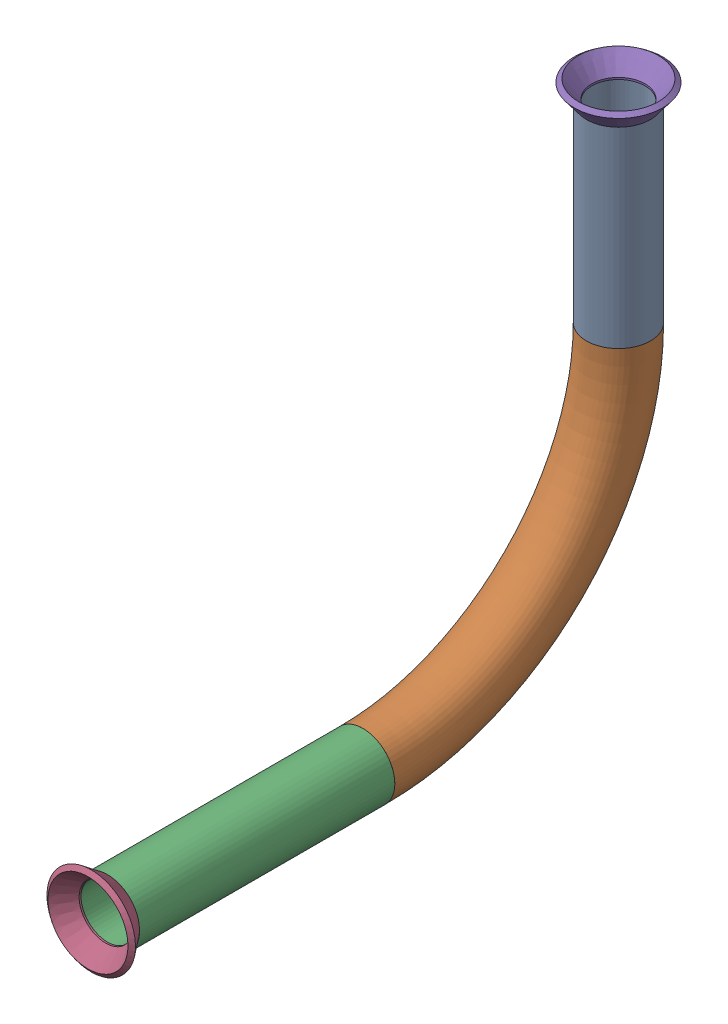
SolidWorks assembly Pipe 32, configuration Default. Lengths in mm.
Overall size (17.59 101.38 114.23).
3 component instances, 2 part files, 1 mates.
Components (placement in the parent):
- Part1-1: Part1 [Default<As Machined>] at origin size (12.7 95.25 107.9)
- Flared pipe end - .5 inch-2: Flared pipe end - .5 inch [Default<As Machined>] at (0 -276.3764 360.7276) x (1 -0.00017 0) z (0 0 1) size (17.59 17.59 3.89)
- Flared pipe end - .5 inch-3: Flared pipe end - .5 inch [Default<As Machined>] at (0 -187.6805 259.1796) x (0 0 1) z (0 1 0) size (17.59 17.59 3.89)
Mates (geometry in assembly coordinates):
- Coincident1719: coincident: circle of Part1-1; circle of Flared pipe end - .5 inch-3
